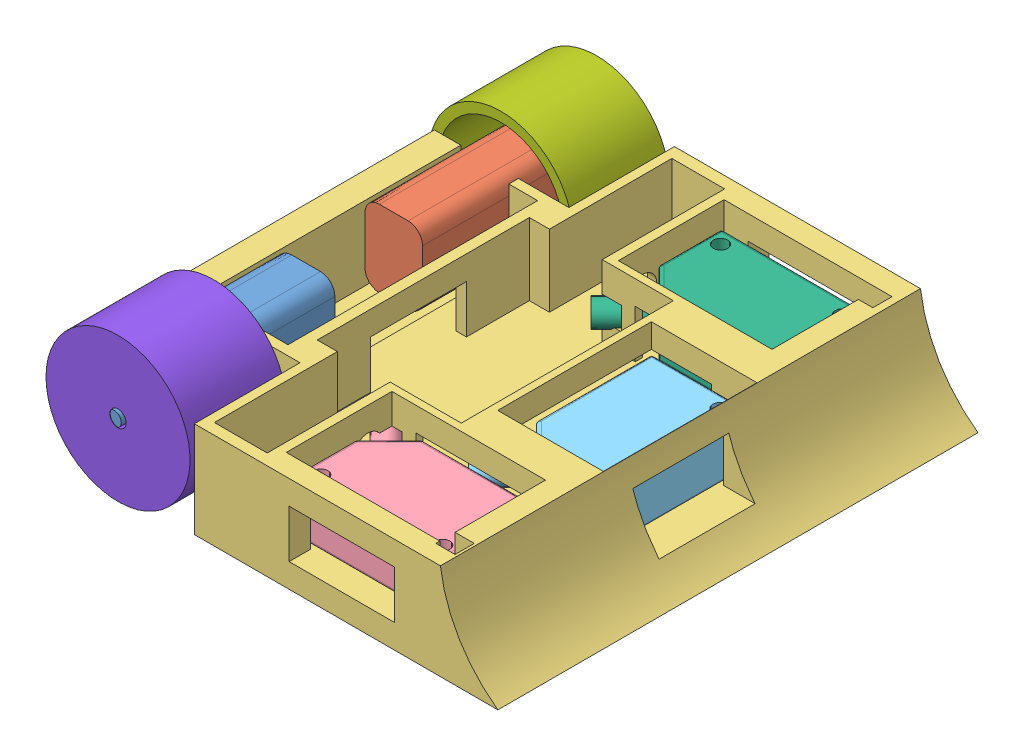
SolidWorks assembly minisumo, configuration Default. Lengths in mm.
Overall size (94.88 30.48 100.77).
8 component instances, 8 part files, 0 mates.
Components (placement in the parent):
- 16mm motor-1: 16mm motor [Default] at (-24.1236 38.3203 55.9323) x (0 0 1) z (0 -1 0) size (40 12 16)
- 16mm motor 2-1: 16mm motor 2 [Default] at (-36.1519 38.3129 7.6504) x (0 0 -1) z (0 -1 0) size (40 12 16)
- 3 omron şasi-1: 3 omron şasi [Default] at (3.3821 25.5139 30.7208) size (91.23 20 100)
- omron2-1: omron2 [Default] at (16.9145 30.1775 65.2202) x (-1 0 0) z (0 0 -1) size (37.72 10.8 25.16)
- omron3-1: omron3 [Default] at (26.6582 30.0164 31.2237) x (0 0 1) z (-1 0 0) size (37.72 10.8 25.16)
- omron4-1: omron4 [Default] at (17.0791 41.09 -3.8827) x (-1 0 0) z (0 0 1) size (37.72 10.8 25.16)
- tekerlek-1: tekerlek [Default] at (-30.2604 38.3254 0.2292) x (0 0 -1) z (1 0 0) size (20 30 30)
- tekerlek2-1: tekerlek2 [Default] at (-29.2451 38.8013 60.9942) x (0 0 1) z (-1 0 0) size (20 30 30)
